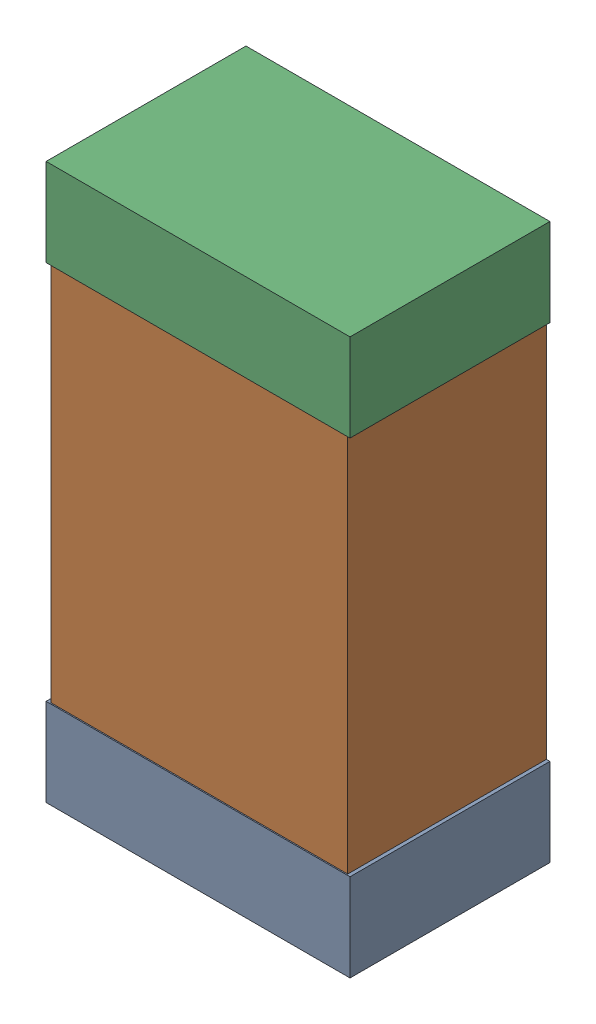
SolidWorks assembly C25Kanaloa_v2.0.0_Power, configuration Default. Lengths in mm.
Overall size (1.3 2.38 0.85).
6 component instances, 2 part files, 0 mates.
Components (placement in the parent):
- 330415056-1: 330415056 [Default] at (55.118 160.036 0) size (1.3 0.38 0.85)
  - Extruded_2-1: Extruded_2 [Default] at origin size (1.3 0.38 0.85)
- 352877008-1: 352877008 [Default] at (55.118 161.036 0) size (1.27 2.2 0.85)
  - Extruded_3-1: Extruded_3 [Default] at origin size (1.27 2.2 0.85)
- 330415056-2: 330415056 [Default] at (55.118 162.036 0) size (1.3 0.38 0.85)
  - Extruded_2-1: Extruded_2 [Default] at origin size (1.3 0.38 0.85)
